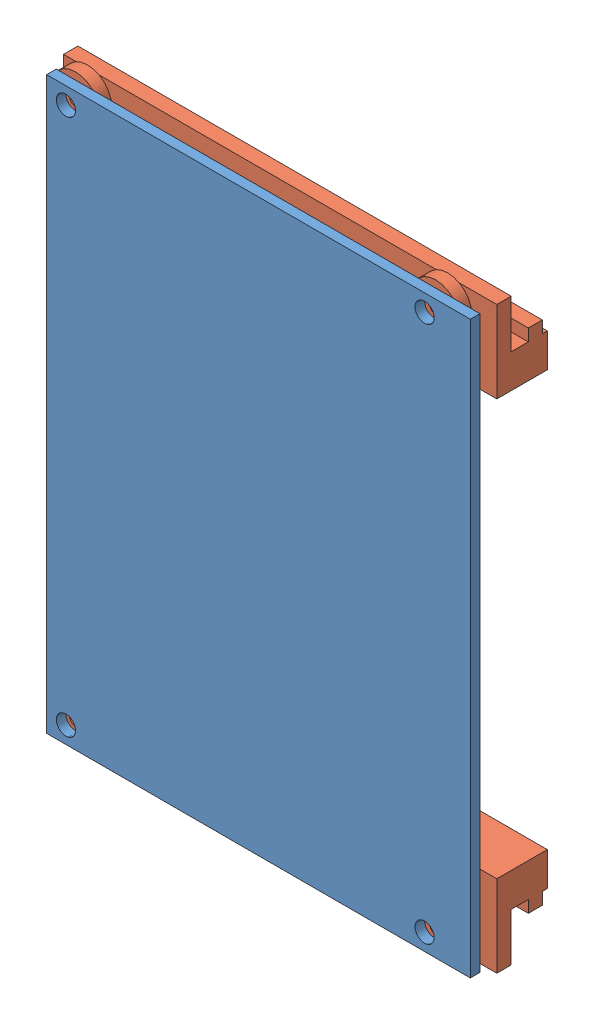
SolidWorks assembly MotorBoard32_BigRobot_WithSupport, configuration Default. Lengths in mm.
Overall size (90 121.5 15).
3 component instances, 2 part files, 6 mates.
Components (placement in the parent):
- MotorBoard32-1: MotorBoard32 [Défaut] at (-10.6888 77.5617 108.2591) size (88 118.5 2)
- MotorBoardElectronicalSupportForBigRobot-1: MotorBoardElectronicalSupportForBigRobot [Left] at (34.3112 27.4117 132.2591) x (0 1 0) z (-1 0 0) size (17.6 13 90)
- MotorBoardElectronicalSupportForBigRobot-2: MotorBoardElectronicalSupportForBigRobot [Right] at (34.3112 127.7117 95.2591) x (0 -1 0) z (-1 0 0) size (17.6 13 90)
Mates (geometry in assembly coordinates):
- Coincident2: coincident: plane of MotorBoard32-1 through (-10.6888 77.5617 108.2591) normal (0 0 -1); plane of MotorBoardElectronicalSupportForBigRobot-1 through (-50.6888 21.8117 108.2591) normal (0 0 1)
- Concentric1: concentric: cylinder of MotorBoard32-1 through (-50.6888 21.8117 108.2591) axis (0 0 1) radius 2; circle of MotorBoardElectronicalSupportForBigRobot-1
- Parallel1: parallel aligned: plane of MotorBoard32-1 through (-54.6888 18.3117 110.2591) normal (0 -1 0); plane of MotorBoardElectronicalSupportForBigRobot-1 through (-55.6888 17.4117 105.7591) normal (0 -1 0)
- Concentric2: concentric: cylinder of MotorBoard32-1 through (-50.6888 133.3117 108.2591) axis (0 0 1) radius 2; cylinder of MotorBoardElectronicalSupportForBigRobot-2 through (-50.6888 133.3117 95.2591) axis (0 0 1) radius 1.25
- Coincident4: coincident: plane of MotorBoard32-1 through (-10.6888 77.5617 108.2591) normal (0 0 -1); plane of MotorBoardElectronicalSupportForBigRobot-2 through (-50.6888 133.3117 108.2591) normal (0 0 1)
- Parallel2: parallel aligned: plane of MotorBoard32-1 through (-54.6888 136.8117 110.2591) normal (0 1 0); plane of MotorBoardElectronicalSupportForBigRobot-2 through (-55.6888 137.7117 105.7591) normal (0 1 0)
